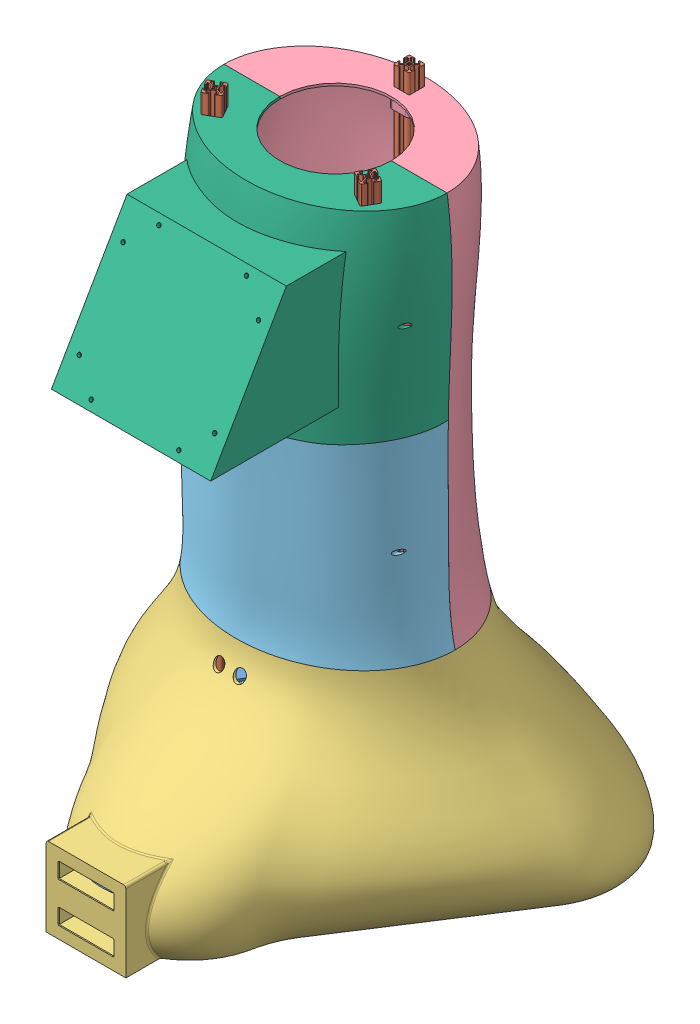
SolidWorks assembly base_12.2, configuration Default. Lengths in mm.
Overall size (552.71 766.01 545.16).
8 component instances, 6 part files, 21 mates.
Components (placement in the parent):
- base_plate_corrected.1-1: base_plate_corrected.1 [Default] at (240.8804 220.7308 359.9783) size (518.75 3 475)
- spine _support-1: spine _support [Default<As Machined>] at (240.8804 603.7308 267.4759) size (20 760 20)
- spine _support-2: spine _support [Default<As Machined>] at (337.2614 603.7308 415.6239) x (0.866025 0 0.5) z (-0.5 0 0.866025) size (20 760 20)
- spine _support-3: spine _support [Default<As Machined>] at (144.5122 603.7308 415.6125) x (0.866025 0 -0.5) z (0.5 0 0.866025) size (20 760 20)
- BASE_LOWER-1: BASE_LOWER [Default] at (240.8804 588.7308 359.9783) x (-1 0 0) z (0 0 -1) size (552.71 251.96 545.16)
- BASE_UPPER_FRONT-1: BASE_UPPER_FRONT [Default] at (240.8804 588.7308 359.9783) x (-1 0 0) z (0 0 -1) size (382.4 494.92 145.32)
- BASE_UPPER_BACK_BOT-1: BASE_UPPER_BACK_BOT [Default] at (240.8806 588.7308 359.9783) x (-1 0 0) z (0 0 -1) size (374.5 255.63 159.69)
- BASE_UPPER_BACK_TOP-1: BASE_UPPER_BACK_TOP [Default] at (240.8804 588.7308 359.9783) x (-1 0 0) z (0 0 -1) size (344.81 254.19 270.47)
Mates (geometry in assembly coordinates):
- Width1: width anti-aligned: plane of base_plate_corrected.1-1 through (227.8804 213.7308 266.4759) normal (0 0 1); plane of base_plate_corrected.1-1 through (227.8804 213.7308 268.4759) normal (0 0 -1); plane of spine _support-1 through (237.7435 223.7308 257.4759) normal (0 0 -1); plane of spine _support-1 through (232.379 223.7308 277.4759) normal (0 0 1)
- Width2: width anti-aligned: plane of base_plate_corrected.1-1 through (239.8804 213.7308 280.4759) normal (1 0 0); plane of base_plate_corrected.1-1 through (241.8804 213.7308 280.4759) normal (-1 0 0); plane of spine _support-1 through (230.8804 223.7308 270.6128) normal (-1 0 0); plane of spine _support-1 through (250.8804 223.7308 275.9773) normal (1 0 0)
- Width3: width anti-aligned: plane of base_plate_corrected.1-1 through (132.7538 213.7308 421.2465) normal (0.5 0 0.866025); plane of base_plate_corrected.1-1 through (133.7538 213.7308 422.9786) normal (-0.5 0 -0.866025); plane of spine _support-3 through (136.7955 223.7308 408.5207) normal (-0.5 0 -0.866025); plane of spine _support-3 through (142.1497 223.7308 428.5235) normal (0.5 0 0.866025)
- Width4: width anti-aligned: plane of base_plate_corrected.1-1 through (138.8782 213.7308 403.8542) normal (-0.866025 0 0.5); plane of base_plate_corrected.1-1 through (137.1461 213.7308 404.8542) normal (0.866025 0 -0.5); plane of spine _support-3 through (151.604 223.7308 407.8959) normal (0.866025 0 -0.5); plane of spine _support-3 through (131.6012 223.7308 413.2501) normal (-0.866025 0 0.5)
- Width5: width anti-aligned: plane of base_plate_corrected.1-1 through (349.0198 213.7308 421.2579) normal (-0.5 0 0.866025); plane of base_plate_corrected.1-1 through (348.0198 213.7308 422.9899) normal (0.5 0 -0.866025); plane of spine _support-2 through (349.6239 223.7308 411.2143) normal (0.5 0 -0.866025); plane of spine _support-2 through (334.9781 223.7308 425.8526) normal (-0.5 0 0.866025)
- Width6: width anti-aligned: plane of spine _support-2 through (327.0327 223.7308 413.3405) normal (-0.866025 0 -0.5); plane of spine _support-2 through (341.671 223.7308 427.9863) normal (0.866025 0 0.5); plane of base_plate_corrected.1-1 through (329.8954 213.7308 426.3822) normal (0.866025 0 0.5); plane of base_plate_corrected.1-1 through (331.6275 213.7308 427.3822) normal (-0.866025 0 -0.5)
- Coincident1: coincident anti-aligned: plane of base_plate_corrected.1-1 through (240.8804 223.7308 359.9783) normal (0 1 0); plane of spine _support-1 through (249.8898 223.7308 270.6128) normal (0 -1 0)
- Coincident2: coincident anti-aligned: plane of base_plate_corrected.1-1 through (240.8804 223.7308 359.9783) normal (0 1 0); plane of spine _support-3 through (153.883 223.7308 413.8245) normal (0 -1 0)
- Coincident3: coincident anti-aligned: plane of base_plate_corrected.1-1 through (240.8804 223.7308 359.9783) normal (0 1 0); plane of spine _support-2 through (343.4954 223.7308 422.8452) normal (0 -1 0)
- Coincident4: coincident anti-aligned: plane of base_plate_corrected.1-1 through (240.8804 220.7308 359.9783) normal (0 -1 0); plane of BASE_LOWER-1 through (24.8388 220.7308 584.857) normal (0 1 0)
- Concentric1: concentric anti-aligned: cylinder of base_plate_corrected.1-1 through (4.3724 131.7308 226.0118) axis (0 1 0) radius 2; cylinder of BASE_LOWER-1 through (4.3724 220.7308 226.0118) axis (0 -1 0) radius 2
- Concentric2: concentric anti-aligned: cylinder of base_plate_corrected.1-1 through (477.3883 131.7308 226.0118) axis (0 1 0) radius 2; cylinder of BASE_LOWER-1 through (477.3883 220.7308 226.0118) axis (0 -1 0) radius 2
- Concentric3: concentric anti-aligned: cylinder of BASE_LOWER-1 through (101.4718 428.7308 354.9783) axis (0 1 0) radius 1.5; cylinder of BASE_UPPER_FRONT-1 through (101.4718 487.7308 354.9783) axis (0 -1 0) radius 1.5
- Concentric4: concentric anti-aligned: cylinder of BASE_LOWER-1 through (380.313 428.7308 354.9783) axis (0 1 0) radius 1.5; cylinder of BASE_UPPER_FRONT-1 through (380.313 487.7308 354.9783) axis (0 -1 0) radius 1.5
- Coincident5: coincident anti-aligned: plane of BASE_LOWER-1 through (240.8804 467.7308 359.9783) normal (0 1 0); plane of BASE_UPPER_FRONT-1 through (240.8804 467.7308 359.9783) normal (0 -1 0)
- Concentric5: concentric anti-aligned: cylinder of BASE_UPPER_FRONT-1 through (109.8103 590.7308 349.9783) axis (0 0 1) radius 1.5; cylinder of BASE_UPPER_BACK_BOT-1 through (109.8103 590.7308 369.9783) axis (0 0 -1) radius 1.5
- Concentric6: concentric anti-aligned: cylinder of BASE_UPPER_FRONT-1 through (372.2501 590.7308 349.9783) axis (0 0 1) radius 1.5; cylinder of BASE_UPPER_BACK_BOT-1 through (372.2504 590.7308 369.9783) axis (0 0 -1) radius 1.5
- Coincident6: coincident anti-aligned: plane of BASE_UPPER_FRONT-1 through (240.8804 588.7308 359.9783) normal (0 0 1); plane of BASE_UPPER_BACK_BOT-1 through (240.8806 588.7308 359.9783) normal (0 0 -1)
- Concentric7: concentric anti-aligned: cylinder of BASE_UPPER_FRONT-1 through (376.2715 836.7308 349.9783) axis (0 0 1) radius 1.5; cylinder of BASE_UPPER_BACK_TOP-1 through (376.2715 836.7308 369.9783) axis (0 0 -1) radius 1.5
- Concentric8: concentric anti-aligned: cylinder of BASE_UPPER_FRONT-1 through (105.3958 836.7308 349.9783) axis (0 0 1) radius 1.5; cylinder of BASE_UPPER_BACK_TOP-1 through (105.3958 836.7308 369.9783) axis (0 0 -1) radius 1.5
- Coincident7: coincident anti-aligned: plane of BASE_UPPER_FRONT-1 through (240.8804 588.7308 359.9783) normal (0 0 1); plane of BASE_UPPER_BACK_TOP-1 through (383.7341 835.2516 359.9783) normal (0 0 -1)
